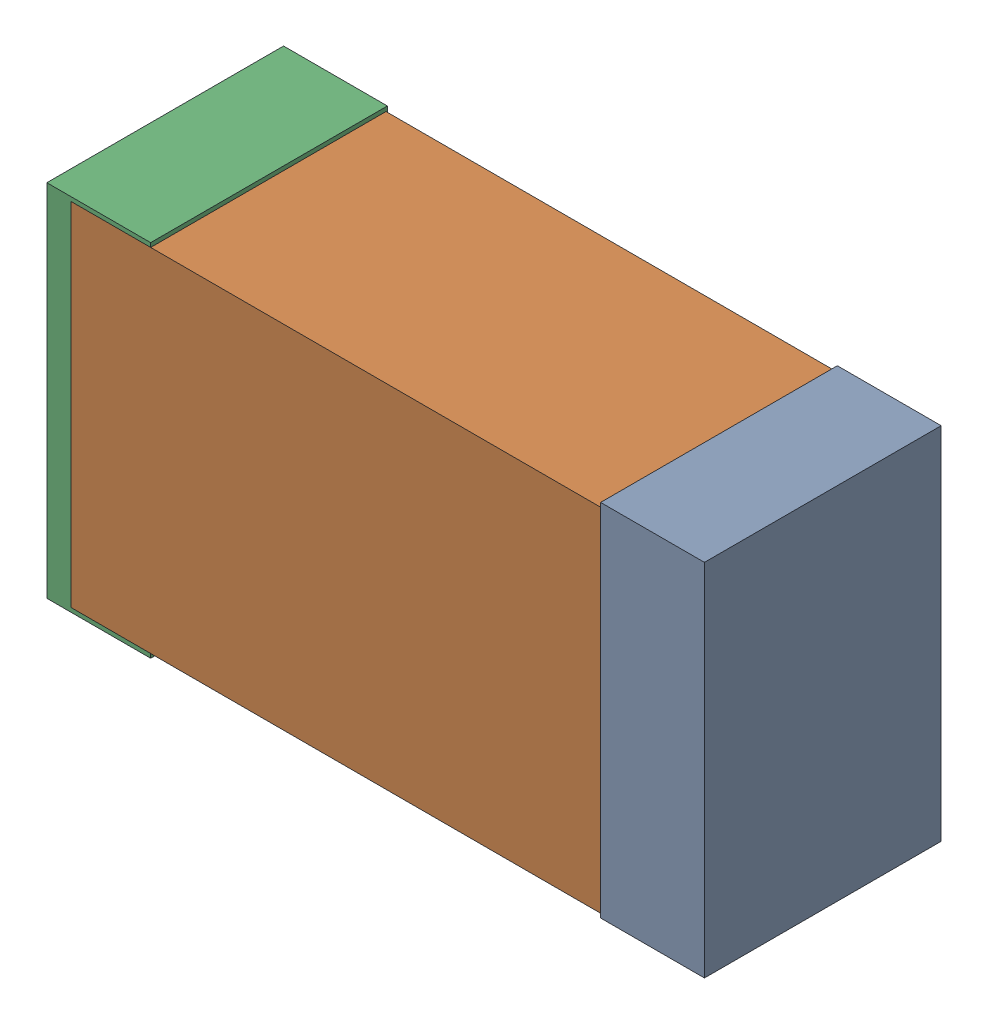
SolidWorks assembly USB23_FB2, configuration Default. Lengths in mm.
Overall size (2.38 1.3 0.85).
6 component instances, 2 part files, 0 mates.
Components (placement in the parent):
- 384311232-1: 384311232 [Default] at (163.814 56.515 -1.9574) size (0.38 1.3 0.85)
  - Extruded_8-1: Extruded_8 [Default] at origin size (0.38 1.3 0.85)
- 402662800-1: 402662800 [Default] at (162.814 56.515 -1.9524) size (2.2 1.27 0.85)
  - Extruded_30-1: Extruded_30 [Default] at origin size (2.2 1.27 0.85)
- 384311232-2: 384311232 [Default] at (161.814 56.515 -1.9574) size (0.38 1.3 0.85)
  - Extruded_8-1: Extruded_8 [Default] at origin size (0.38 1.3 0.85)
